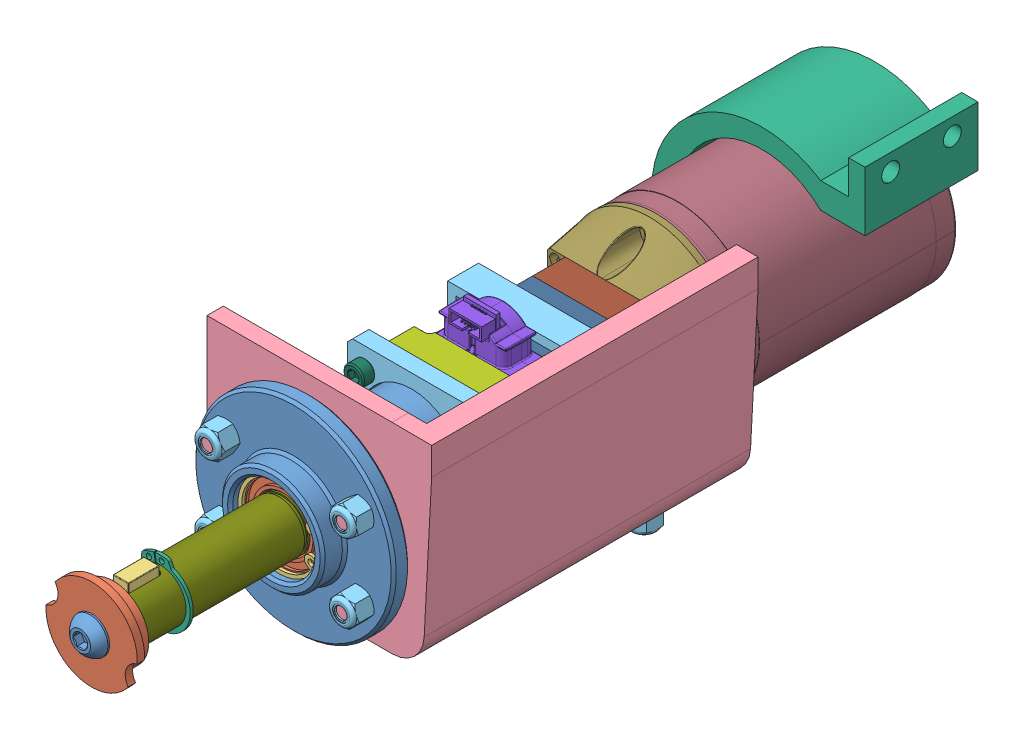
SolidWorks assembly assemblage moteur et sol, configuration Default. Lengths in mm.
Overall size (163.91 93.83 344.65).
43 component instances, 24 part files, 0 mates.
Components (placement in the parent):
- PB2023-M054 DRIVETRAIN ASSEMBLY-v1-1: PB2023-M054 DRIVETRAIN ASSEMBLY-v1 [Default] at (194.4247 468.0978 914.4535) x (0 1 0) z (0 0 1) size (93.83 163.91 344.65)
  - A12220103_FRONT_BRACKET_ASSEMBLY-1: A12220103_FRONT_BRACKET_ASSEMBLY [Default] at origin size (78 78 534.65)
    - A12220101_FRONT_CASE_ASSEMBLY-1: A12220101_FRONT_CASE_ASSEMBLY [Default] at origin size (78 78 141.2)
      - 12220103_FRONT_HOUSING-1: 12220103_FRONT_HOUSING [Default] at (-52 141.0744 -192.9876) x (0 0 -1) z (1 0 0) size (60 78 78)
      - BALL BEARING-1: BALL BEARING [6656K203] at origin size (32 32 10)
      - BALL BEARING-2: BALL BEARING [6656K203] at (0 0 41) size (32 32 10)
      - Internal Retaining Ring (98455A129)-1: Internal Retaining Ring (98455A129) [98455A129] at (0.0361 0.7992 46) x (0.998982 -0.045107 0) z (0 0 1) size (34.4 33.81 1.2)
    - M6 x 20mm Steel Hex Head Screw (91310A333)-2: M6 x 20mm Steel Hex Head Screw (91310A333) [91310A333] at (-15.125 -26.1973 37.15) x (0 0 1) z (-0.44141 0.897306 0) size (24.4 11.55 10)
    - M6 x 1mm Steel Hex LockNut (90592A016)-1: M6 x 1mm Steel Hex LockNut (90592A016) [97260A101] at (15.125 -26.1973 41.85) x (0.928554 -0.371196 0) z (-0.371196 -0.928554 0) size (10 8.38 11.55)
    - 20MM External Retaining Ring (98541A123)-4: 20MM External Retaining Ring (98541A123) [98541A123] at (0 0 92.94) x (0 0 1) z (-0.186581 0.98244 0) size (1.2 25.1 22.76)
    - A12220110_FRONT_SHAFT_ASSEMBLY-1: A12220110_FRONT_SHAFT_ASSEMBLY [Default] at (1.7896 0 -19.01) x (0 -1 0) z (0 0 1) size (64.01 67.32 307.03)
      - A12220105_MOTOR_BRACKET_ASSEMBLY-1: A12220105_MOTOR_BRACKET_ASSEMBLY [Default] at origin size (64.01 67.32 280.24) (flexible)
        - 12220106-051 MiniCIM Motor Assembly-1: 12220106-051 MiniCIM Motor Assembly [Default] at origin size (64.01 67.32 218.97)
          - Gearbox Assembly-1: Gearbox Assembly [Default] at (34.0244 -12.4567 -92.7758) x (0 0 1) z (-1 0 0) size (123.35 56.32 44.45)
            - Output Housing-2: Output Housing [Default] at (64.8023 -0.856 18.2213) x (1 0 0) z (0 -1 0) size (75.7 44.45 56.32)
              - Housing-1: Housing [Default] at (19.8785 -6.4219 -11.5232) size (18.13 44.45 42)
              - Encoder.step-1: Encoder.step [Default] at (12.6785 15.8031 -11.5232) x (0 0 1) z (-1 0 0) size (56.32 42 21.21)
              - Gearbox_output_shaft-1: Gearbox_output_shaft [Default] at origin size (63.51 17 17)
            - Ring Gears-1: Ring Gears [Default] at (71.9808 10.6671 11.7994) x (1 0 0) z (0 -1 0) size (32.2 42 42)
            - Ring Gear Stage 3-1: Ring Gear Stage 3 [Default] at (59.2808 10.6671 11.7994) x (1 0 0) z (0 -1 0) size (28.65 42 42)
          - CIM Adaptor.step-1: CIM Adaptor.step [Default] at (0 -1.7896 -68.72) x (0 -1 0) z (-1 0 0) size (64.01 21.63 64.01)
          - Mini CIM-1: Mini CIM [Default] at (0 -1.7896 -80.245) x (0 0 -1) z (1 0 0) size (101.22 64.01 64.01)
          - 8-32 X 3IN LG - Black-Oxide Alloy Steel Socket Head Screw (90044A516)-1: 8-32 X 3IN LG - Black-Oxide Alloy Steel Socket Head Screw (90044A516) [90044A516] at (17.5 15.7104 -75.245) x (-0.08536 0.99635 0) z (0 0 -1) size (6.86 6.86 81.33)
          - 8-32 X 3IN LG - Black-Oxide Alloy Steel Socket Head Screw (90044A516)-3: 8-32 X 3IN LG - Black-Oxide Alloy Steel Socket Head Screw (90044A516) [90044A516] at (-17.5 -19.2896 -75.245) x (-0.242255 0.970213 0) z (0 0 -1) size (6.86 6.86 81.33)
        - 10-32 X 0.875IN LG - Black-Oxide Alloy Steel Socket Head Screw (91251A346)-1: 10-32 X 0.875IN LG - Black-Oxide Alloy Steel Socket Head Screw (91251A346) [91251A346] at (-17.9605 16.1709 6.1805) x (0.130335 0.99147 0) z (0 0 1) size (7.94 7.94 27.67)
        - 10-32 X 0.875IN LG - Black-Oxide Alloy Steel Socket Head Screw (91251A346)-2: 10-32 X 0.875IN LG - Black-Oxide Alloy Steel Socket Head Screw (91251A346) [91251A346] at (17.9605 -19.7501 6.1805) x (0.872398 0.488796 0) z (0 0 1) size (7.94 7.94 27.67)
      - PB2023-M005 ROTARY SHAFT-1: PB2023-M005 ROTARY SHAFT [Default] at (0 -1.7896 136.57) x (0 0 -1) z (1 0 0) size (126.56 25 25)
      - 12220110_MOTOR_KEY-1: 12220110_MOTOR_KEY [Default] at (0 5.1764 16.3975) size (3.17 4.76 26.16)
    - M6 x 20mm Steel Hex Head Screw (91310A333)-7: M6 x 20mm Steel Hex Head Screw (91310A333) [91310A333] at (15.125 -26.1973 37.15) x (0 0 1) z (0.78025 0.625468 0) size (24.4 11.55 10)
    - M6 x 20mm Steel Hex Head Screw (91310A333)-9: M6 x 20mm Steel Hex Head Screw (91310A333) [91310A333] at (15.125 26.1973 37.15) x (0 0 1) z (0.877007 0.480477 0) size (24.4 11.55 10)
    - M6 x 20mm Steel Hex Head Screw (91310A333)-11: M6 x 20mm Steel Hex Head Screw (91310A333) [91310A333] at (-15.0958 26.1466 37.15) x (0 0 1) z (0.947118 0.320887 0) size (24.4 11.55 10)
    - M6 x 1mm Steel Hex LockNut (90592A016)-7: M6 x 1mm Steel Hex LockNut (90592A016) [97260A101] at (-15.125 -26.1973 41.85) x (0.975663 -0.219276 0) z (-0.219276 -0.975663 0) size (10 8.38 11.55)
    - M6 x 1mm Steel Hex LockNut (90592A016)-9: M6 x 1mm Steel Hex LockNut (90592A016) [97260A101] at (-15.125 26.1973 41.85) x (0.995642 -0.093258 0) z (-0.093258 -0.995642 0) size (10 8.38 11.55)
    - M6 x 1mm Steel Hex LockNut (90592A016)-11: M6 x 1mm Steel Hex LockNut (90592A016) [97260A101] at (15.2049 26.151 41.85) x (1 -0.000046 0) z (-0.000046 -1 0) size (10 8.38 11.55)
  - M6 x 25mm Steel Socket Head Screw (91290A330)-1: M6 x 25mm Steel Socket Head Screw (91290A330) [91290A330] at (-31.155 30 -64.48) x (0 -0.901175 -0.433456) z (1 0 0) size (10 10 31.46)
  - M6 x 1mm Steel Hex LockNut (90592A016)-1: M6 x 1mm Steel Hex LockNut (90592A016) [97260A101] at (-33 -30 -64.48) x (0 0.608626 0.793457) z (0 -0.793457 0.608626) size (10 8.38 11.55)
  - M6 x 1mm Steel Hex LockNut (90592A016)-2: M6 x 1mm Steel Hex LockNut (90592A016) [97260A101] at (-33 30 -64.48) x (0 -0.994883 0.101031) z (0 -0.101031 -0.994883) size (10 8.38 11.55)
  - M8 X 20MM - 18-8 Stainless Steel Button Head Hex Drive Screws (97763A444)-1: M8 X 20MM - 18-8 Stainless Steel Button Head Hex Drive Screws (97763A444) [97763A444] at (0 0 124.825) x (0.999813 0.019347 0) z (0 0 1) size (14 14 25.15)
  - PB2023-M006 WHEEL END CAP CUSTOM WASHER-1: PB2023-M006 WHEEL END CAP CUSTOM WASHER [Default] at (0 0 117.56) x (0 0 -1) z (-0.345262 -0.938506 0) size (8.5 35.5 34.05)
  - 98870A743_Machine Key-1: 98870A743_Machine Key [98870A743] at (10 0 103.06) size (6 6 12)
  - braquette bleu-1: braquette bleu [Default] at (-33 40 35.5) x (0 0 -1) z (0 -1 0) size (205.75 78 138.28)
  - braquette gearbox-3: braquette gearbox [Default] at (-21.66 25 -4.13) x (0 0 -1) z (-1 0 0) size (72.34 80.66 66.5)
  - braquette moteur- v2-1: braquette moteur- v2 [Default] at (0 -0.0033 -184.471) x (0 1 0) z (0 0 -1) size (123.62 80 44)
